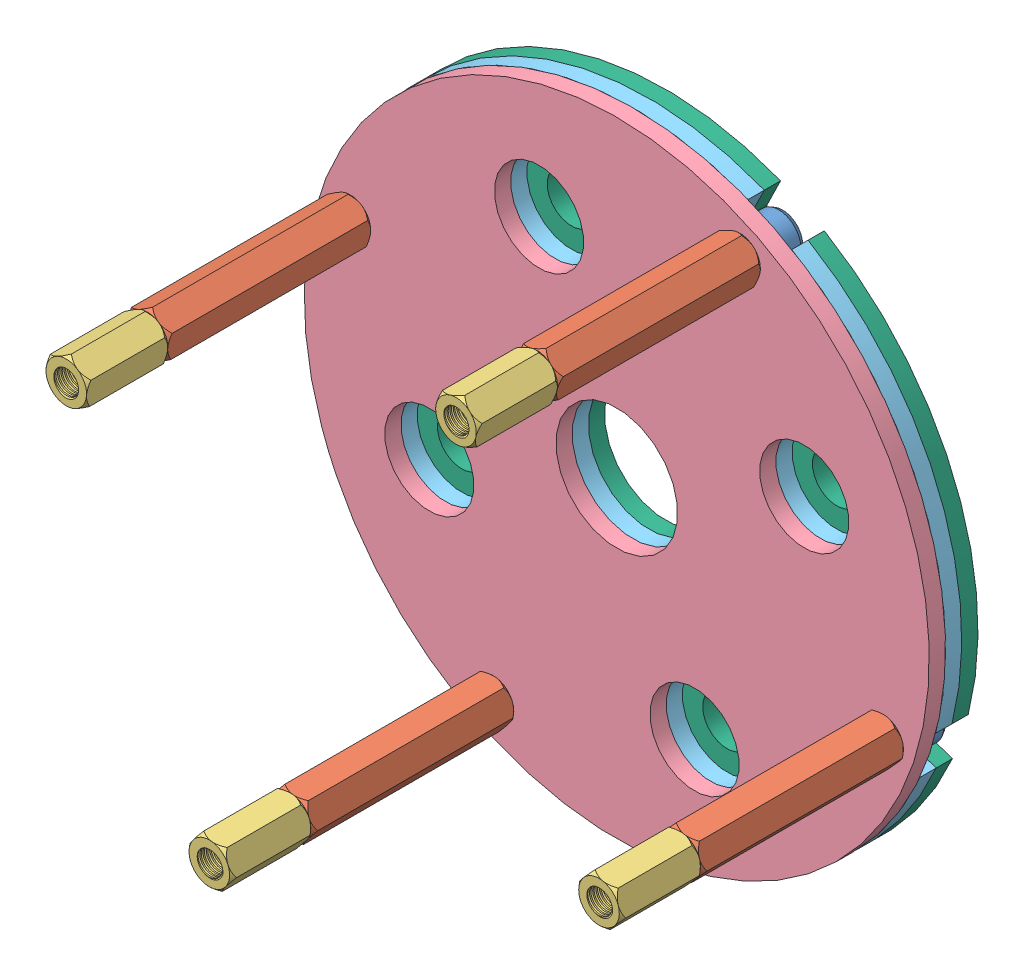
SolidWorks assembly FlangeStdServo, configuration Default. Lengths in mm.
Overall size (100.62 100.62 41.15).
15 component instances, 6 part files, 36 mates.
Components (placement in the parent):
- M3x10-1: M3x10 [Default] at (-2227.3141 -1362.9914 208.7081) x (-0.439147 0.898415 0) z (-0.898415 -0.439147 0) size (5.5 13.21 5.5)
- M3x10-2: M3x10 [Default] at (-2275.3101 -1382.9682 208.7081) x (0.998756 -0.049868 0) z (0.049868 0.998756 0) size (5.5 13.21 5.5)
- M3x10-3: M3x10 [Default] at (-2292.9304 -1340.4767 208.7081) x (-0.999751 -0.022302 0) z (0.022302 -0.999751 0) size (5.5 13.21 5.5)
- M3x10-4: M3x10 [Default] at (-2244.8821 -1320.6261 208.7081) x (-0.21891 -0.975745 0) z (0.975745 -0.21891 0) size (5.5 13.21 5.5)
- M3Spacer25-1: M3Spacer25 [Default] at (-2227.3118 -1363.0644 210.7081) x (-0.658508 -0.752574 0) z (-0.752574 0.658508 0) size (6.28 25.53 5)
- M3Spacer25-2: M3Spacer25 [Default] at (-2244.9321 -1320.5729 210.7081) x (-0.955483 -0.295047 0) z (-0.295047 0.955483 0) size (6.28 25.53 5)
- M3Spacer25-3: M3Spacer25 [Default] at (-2275.3101 -1382.9682 210.7081) x (0.993185 -0.11655 0) z (-0.11655 -0.993185 0) size (6.28 25.53 5)
- M3Spacer25-4: M3Spacer25 [Default] at (-2292.9304 -1340.4767 210.7081) x (-0.893808 -0.44845 0) z (-0.44845 0.893808 0) size (6.28 25.53 5)
- M3Spacer10-1: M3Spacer10 [Default] at (-2227.3118 -1363.0644 245.7081) x (-0.981002 0.193998 0) z (-0.193998 -0.981002 0) size (6.28 16.65 5)
- M3Spacer10-2: M3Spacer10 [Default] at (-2244.9321 -1320.5729 245.7081) x (-0.733259 0.679949 0) z (-0.679949 -0.733259 0) size (6.28 16.65 5)
- M3Spacer10-3: M3Spacer10 [Default] at (-2275.3101 -1382.9682 245.7081) x (-0.993185 0.11655 0) z (-0.11655 -0.993185 0) size (6.28 16.65 5)
- M3Spacer10-4: M3Spacer10 [Default] at (-2292.9304 -1340.4767 245.7081) x (0.058535 0.998285 0) z (-0.998285 0.058535 0) size (6.28 16.65 5)
- flangeStdServo_1-1: flangeStdServo_1 [Default] at (-2260.1211 -1351.7705 210.7081) x (-0.923728 -0.383049 0) z (0 0 -1) size (77 77 2)
- flangeStdServo_2-1: flangeStdServo_2 [Default] at (-2260.1211 -1351.7705 208.7081) x (-0.923728 -0.383049 0) z (0 0 -1) size (77 77 2)
- flangeStdServo_3-1: flangeStdServo_3 [Default] at (-2260.1211 -1351.7705 206.7081) x (-0.923728 -0.383049 0) z (0 0 -1) size (77 77 2)
Mates (geometry in assembly coordinates):
- Concentric10: concentric anti-aligned: circle of M3Spacer25-4; circle of M3Spacer10-4
- Concentric12: concentric anti-aligned: circle of M3Spacer25-3; circle of M3Spacer10-3
- Concentric14: concentric anti-aligned: circle of M3Spacer25-2; circle of M3Spacer10-2
- Concentric16: concentric anti-aligned: circle of M3Spacer25-1; circle of M3Spacer10-1
- Concentric17: concentric aligned: circle of flangeStdServo_1-1; circle of flangeStdServo_2-1
- Concentric18: concentric aligned: circle of flangeStdServo_1-1; circle of flangeStdServo_3-1
- Concentric19: concentric aligned: circle of flangeStdServo_1-1; circle of flangeStdServo_3-1
- Concentric20: concentric aligned: circle of flangeStdServo_1-1; circle of flangeStdServo_2-1
- Concentric21: concentric aligned: circle of flangeStdServo_1-1; circle of flangeStdServo_2-1
- Concentric22: concentric aligned: circle of flangeStdServo_1-1; circle of flangeStdServo_3-1
- Concentric23: concentric anti-aligned: circle of M3x10-1; circle of flangeStdServo_3-1
- Concentric24: concentric anti-aligned: circle of M3x10-4; circle of flangeStdServo_3-1
- Concentric25: concentric anti-aligned: circle of M3x10-2; circle of flangeStdServo_3-1
- Concentric26: concentric anti-aligned: circle of M3x10-3; circle of flangeStdServo_3-1
- Concentric27: concentric anti-aligned: circle of M3Spacer25-3; circle of flangeStdServo_1-1
- Concentric28: concentric aligned: circle of M3Spacer10-4; circle of flangeStdServo_1-1
- Concentric29: concentric aligned: circle of M3Spacer10-1; circle of flangeStdServo_1-1
- Concentric30: concentric aligned: circle of M3Spacer10-2; circle of flangeStdServo_1-1
- Coincident19: coincident anti-aligned: plane of flangeStdServo_1-1 through (-2260.1211 -1351.7705 208.7081) normal (0 0 -1); plane of flangeStdServo_2-1 through (-2260.1211 -1351.7705 208.7081) normal (0 0 1)
- Coincident20: coincident anti-aligned: plane of flangeStdServo_2-1 through (-2260.1211 -1351.7705 206.7081) normal (0 0 -1); plane of flangeStdServo_3-1 through (-2260.1211 -1351.7705 206.7081) normal (0 0 1)
- Coincident21: coincident anti-aligned: plane of M3Spacer25-2 through (-2244.9321 -1320.5729 235.7081) normal (0 0 1); plane of M3Spacer10-2 through (-2244.9321 -1320.5729 235.7081) normal (0 0 -1)
- Coincident22: coincident anti-aligned: plane of M3Spacer25-4 through (-2292.9304 -1340.4767 235.7081) normal (0 0 1); plane of M3Spacer10-4 through (-2292.9304 -1340.4767 235.7081) normal (0 0 -1)
- Coincident23: coincident anti-aligned: plane of M3Spacer25-3 through (-2275.3101 -1382.9682 235.7081) normal (0 0 1); plane of M3Spacer10-3 through (-2275.3101 -1382.9682 235.7081) normal (0 0 -1)
- Coincident24: coincident anti-aligned: plane of M3Spacer25-1 through (-2227.3118 -1363.0644 235.7081) normal (0 0 1); plane of M3Spacer10-1 through (-2227.3118 -1363.0644 235.7081) normal (0 0 -1)
- Parallel1: parallel aligned: plane of M3Spacer25-1 through (-2225.4109 -1360.8919 235.7081) normal (0.193998 0.981002 0); plane of M3Spacer10-1 through (-2228.2428 -1360.3318 235.7081) normal (0.193998 0.981002 0)
- Parallel2: parallel aligned: plane of M3Spacer25-3 through (-2272.4431 -1383.3046 235.7081) normal (0.918398 0.395658 0); plane of M3Spacer10-3 through (-2273.5852 -1380.6534 235.7081) normal (0.918398 0.395658 0)
- Parallel3: parallel aligned: plane of M3Spacer25-2 through (-2242.1738 -1319.7211 235.7081) normal (0.679949 0.733259 0); plane of M3Spacer10-2 through (-2244.2906 -1317.7583 235.7081) normal (0.679949 0.733259 0)
- Coincident25: coincident aligned: plane of M3Spacer25-4 through (-2292.7614 -1337.5949 235.7081) normal (-0.44845 0.893808 0); plane of M3Spacer10-4 through (-2295.3416 -1338.8894 235.7081) normal (-0.44845 0.893808 0)
- Coincident26: coincident anti-aligned: plane of M3Spacer25-4 through (-2292.9304 -1340.4767 210.7081) normal (0 0 -1); plane of flangeStdServo_1-1 through (-2260.1211 -1351.7705 210.7081) normal (0 0 1)
- Coincident27: coincident anti-aligned: plane of M3Spacer25-3 through (-2275.3101 -1382.9682 210.7081) normal (0 0 -1); plane of flangeStdServo_1-1 through (-2260.1211 -1351.7705 210.7081) normal (0 0 1)
- Coincident28: coincident anti-aligned: plane of M3Spacer25-1 through (-2227.3118 -1363.0644 210.7081) normal (0 0 -1); plane of flangeStdServo_1-1 through (-2260.1211 -1351.7705 210.7081) normal (0 0 1)
- Coincident29: coincident anti-aligned: plane of M3Spacer25-2 through (-2244.9321 -1320.5729 210.7081) normal (0 0 -1); plane of flangeStdServo_1-1 through (-2260.1211 -1351.7705 210.7081) normal (0 0 1)
- Coincident30: coincident anti-aligned: plane of M3x10-3 through (-2292.9304 -1340.4767 208.7081) normal (0 0 1); plane of flangeStdServo_1-1 through (-2260.1211 -1351.7705 208.7081) normal (0 0 -1)
- Coincident31: coincident anti-aligned: plane of M3x10-2 through (-2275.3101 -1382.9682 208.7081) normal (0 0 1); plane of flangeStdServo_1-1 through (-2260.1211 -1351.7705 208.7081) normal (0 0 -1)
- Coincident32: coincident anti-aligned: plane of M3x10-1 through (-2227.3141 -1362.9914 208.7081) normal (0 0 1); plane of flangeStdServo_1-1 through (-2260.1211 -1351.7705 208.7081) normal (0 0 -1)
- Coincident33: coincident anti-aligned: plane of M3x10-4 through (-2244.8821 -1320.6261 208.7081) normal (0 0 1); plane of flangeStdServo_1-1 through (-2260.1211 -1351.7705 208.7081) normal (0 0 -1)
